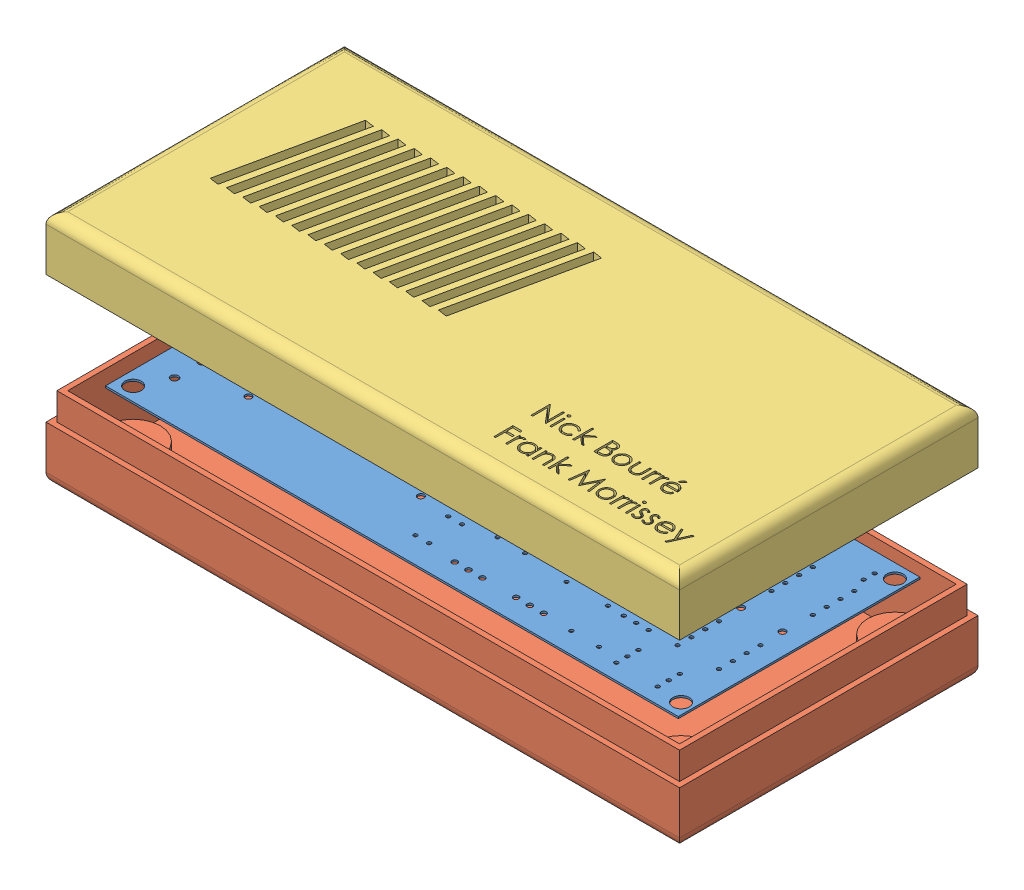
SolidWorks assembly ProjetSession, configuration Défaut. Lengths in mm.
Overall size (116.6 43.52 54.92).
3 component instances, 3 part files, 8 mates.
Components (placement in the parent):
- Board-1: Board [Défaut] at (-62.9699 116.5448 50.5576) x (1 0 0) z (0 1 0) size (105.41 44.45 0.35)
- fond-1: fond [Défaut] at (45.612 100.6902 -7.6084) size (116.6 15 54.92)
- dessus-1: dessus [Défaut] at (45.612 144.2138 13.7897) x (1 0 0) z (0 0 -1) size (116.6 10 54.92)
Mates (geometry in assembly coordinates):
- Coïncidente2: coincident aligned: plane of fond-1 through (-43.1297 110.6902 30.5531) normal (0 0 1); plane of dessus-1 through (-43.1297 134.2138 30.5531) normal (0 0 1)
- Coïncidente3: coincident aligned: plane of fond-1 through (-43.1297 110.6902 -24.3718) normal (-1 0 0); plane of dessus-1 through (-43.1297 134.2138 30.5531) normal (-1 0 0)
- Coïncidente5: coincident aligned: plane of fond-1 through (-43.1297 110.6902 30.5531) normal (0 0 1); plane of dessus-1 through (-43.1297 134.2138 30.5531) normal (0 0 1)
- Coïncidente6: coincident aligned: plane of fond-1 through (73.4677 110.6902 -24.3718) normal (1 0 0); plane of dessus-1 through (73.4677 134.2138 30.5531) normal (1 0 0)
- Coïncidente7: coincident aligned: plane of fond-1 through (-43.1297 110.6902 -24.3718) normal (-1 0 0); plane of dessus-1 through (-43.1297 134.2138 30.5531) normal (-1 0 0)
- Coïncidente8: coincident aligned: plane of fond-1 through (-43.1297 110.6902 -24.3718) normal (0 0 -1); plane of dessus-1 through (-43.1297 134.2138 -24.3718) normal (0 0 -1)
- Coaxiale3: concentric anti-aligned: circle of Board-1; circle of fond-1
- Parallèle2: parallel aligned: plane of Board-1 through (67.8401 116.1994 -19.2924) normal (1 0 0); plane of fond-1 through (73.4677 110.6902 -24.3718) normal (1 0 0)
